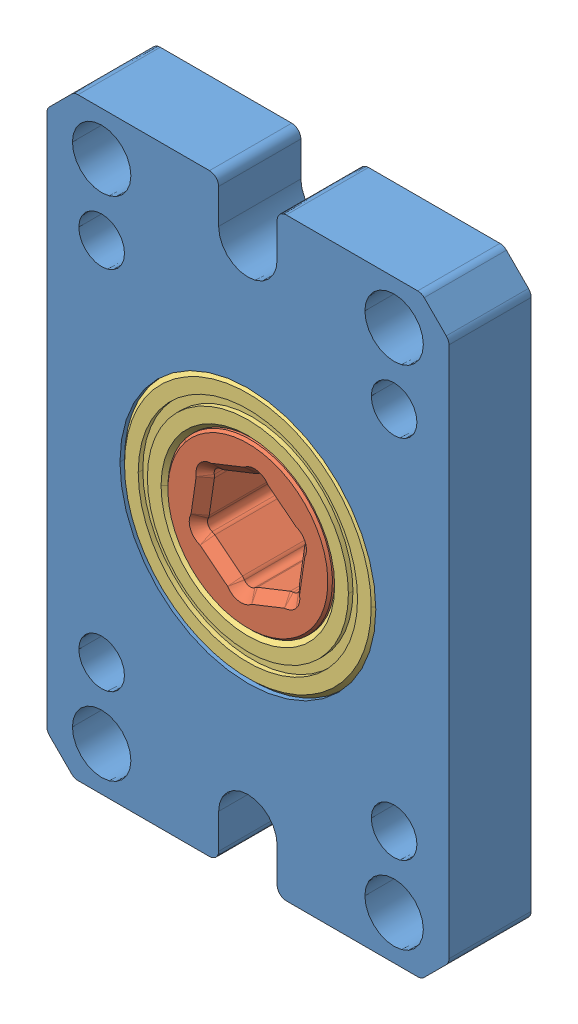
SolidWorks assembly Mancal REV, configuration Valor predeterminado. Lengths in mm.
Overall size (22 32.5 4.5).
3 component instances, 3 part files, 0 mates.
Components (placement in the parent):
- REV-41-1683-1^Mancal REV-1: REV-41-1683-1^Mancal REV [Valor predeterminado] at origin size (22 32.5 4.5) (virtual)
- REV-41-1527^Mancal REV-1: REV-41-1527^Mancal REV [Valor predeterminado] x (0.784162 -0.620556 0) z (0 0 1) size (9 9 4.5) (virtual)
- 679ZZ.STEP-1: 679ZZ.STEP [Valor predeterminado] at (0 0 2.25) size (14 14 4.5)
